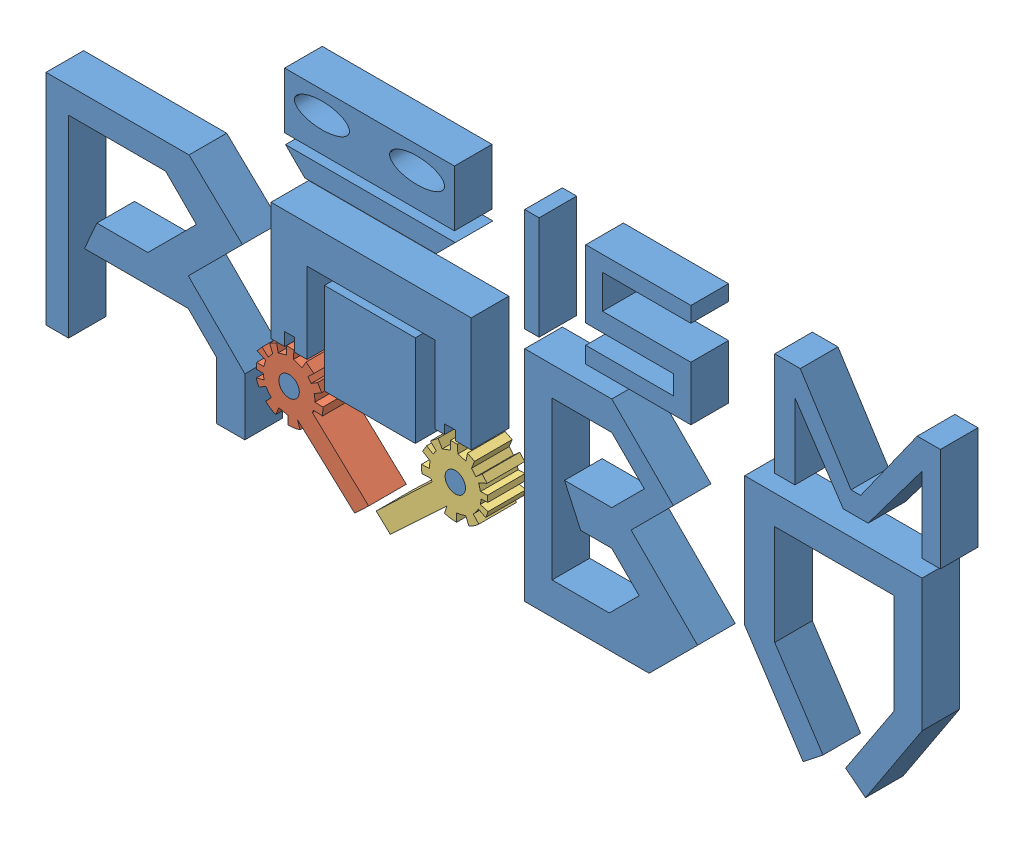
SolidWorks assembly Assem2, configuration Default. Lengths in mm.
Overall size (237.61 93.4 10).
3 component instances, 3 part files, 4 mates.
Components (placement in the parent):
- roboism-2: roboism [Default] at (27.2531 2.5538 238.8411) size (237.61 90.84 10)
- robo1-2: robo1 [Default] at (27.5837 -2.6917 238.8411) x (0.999416 -0.034161 0) z (0 0 1) size (30.33 28.89 10)
- robo3-1: robo3 [Default] at (28.0996 3.7357 238.8411) x (0.999139 0.041498 0) z (0 0 1) size (30.33 28.89 10)
Mates (geometry in assembly coordinates):
- Coincident4: coincident: circle of roboism-2; circle of robo1-2
- Coincident5: coincident: circle of roboism-2; circle of robo3-1
- Coincident6: coincident aligned: circle of roboism-2; circle of robo1-2
- Coincident7: coincident aligned: circle of roboism-2; circle of robo3-1
